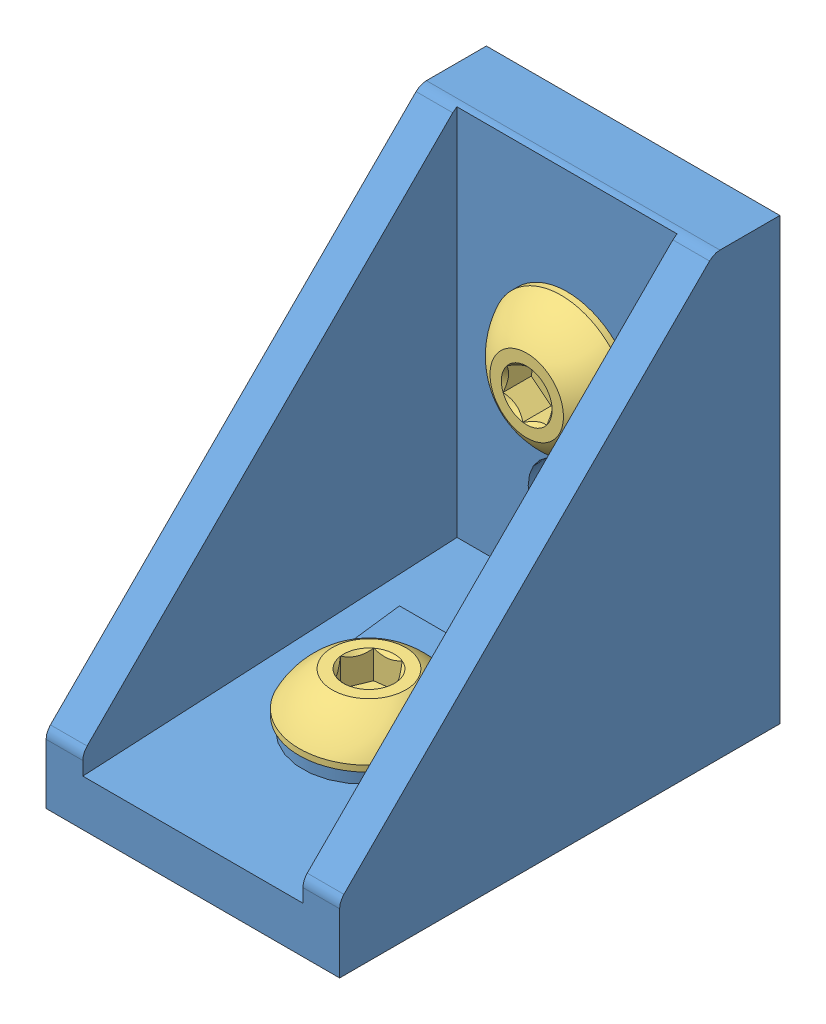
SolidWorks assembly HBLFSNB5_W_Hardware, configuration Default. Lengths in mm.
Overall size (20 35.78 35.78).
5 component instances, 3 part files, 10 mates.
Components (placement in the parent):
- HBLFSNB5-1: HBLFSNB5 [Default] at origin size (20 31 31)
- HNTTSN5-5-1: HNTTSN5-5 [Default] at (0 18 -1.2) x (0 0 1) z (0 -1 0) size (4.3 10 10)
- HNTTSN5-5-2: HNTTSN5-5 [Default] at (0 -1.2 18) x (0 1 0) z (0 0 1) size (4.3 10 10)
- 5mmX10mm_Buttonhead(McMaster_91239A224)-1: 5mmX10mm_Buttonhead(McMaster_91239A224) [91239A224] at (0 18 7.25) x (0.988197 -0.153186 0) z (0 0 1) size (9.5 9.5 13.21)
- 5mmX10mm_Buttonhead(McMaster_91239A224)-3: 5mmX10mm_Buttonhead(McMaster_91239A224) [91239A224] at (0 7.25 18) x (0.130489 0 0.99145) z (0 1 0) size (9.5 9.5 13.21)
Mates (geometry in assembly coordinates):
- Concentric1: concentric anti-aligned: cylinder of HBLFSNB5-1 through (0 18 4.5) axis (0 0 -1) radius 2.65; cylinder of 5mmX10mm_Buttonhead(McMaster_91239A224)-1 through (0 18 7.25) axis (0 0 1) radius 4.75
- Coincident1: coincident anti-aligned: plane of HBLFSNB5-1 through (7.5 4.5 4.5) normal (0 0 1); plane of 5mmX10mm_Buttonhead(McMaster_91239A224)-1 through (-0.7276 13.3061 4.5) normal (0 0 -1)
- Concentric2: concentric anti-aligned: cylinder of HNTTSN5-5-1 through (0 18 -1.2) axis (0 0 -1) radius 2.067; cylinder of 5mmX10mm_Buttonhead(McMaster_91239A224)-1 through (0 18 7.25) axis (0 0 1) radius 4.75
- Parallel1: parallel aligned: plane of HBLFSNB5-1 through (10 30 0) normal (0 1 0); plane of HNTTSN5-5-1 through (0 23 -1.2) normal (0 1 0)
- Distance2: distance = 2 mm anti-aligned: plane of HNTTSN5-5-1 through (5 13 -2) normal (0 0 1); plane of HBLFSNB5-1 through (0 0 0) normal (0 0 -1)
- Concentric3: concentric anti-aligned: cylinder of HBLFSNB5-1 through (0 4.5 18) axis (0 -1 0) radius 2.65; cylinder of 5mmX10mm_Buttonhead(McMaster_91239A224)-3 through (0 7.25 18) axis (0 1 0) radius 4.75
- Coincident5: coincident anti-aligned: plane of HBLFSNB5-1 through (0 4.5 18) normal (0 1 0); plane of 5mmX10mm_Buttonhead(McMaster_91239A224)-3 through (-4.7094 4.5 18.6198) normal (0 -1 0)
- Concentric4: concentric anti-aligned: cylinder of HNTTSN5-5-2 through (0 -1.2 18) axis (0 -1 0) radius 2.067; cylinder of 5mmX10mm_Buttonhead(McMaster_91239A224)-3 through (0 7.25 18) axis (0 1 0) radius 4.75
- Parallel2: parallel aligned: plane of HBLFSNB5-1 through (10 4.0858 30) normal (0 0 1); plane of HNTTSN5-5-2 through (0 -1.2 23) normal (0 0 1)
- Distance3: distance = 2 mm anti-aligned: plane of HNTTSN5-5-2 through (5 -2 23) normal (0 1 0); plane of HBLFSNB5-1 through (0 0 0) normal (0 -1 0)
